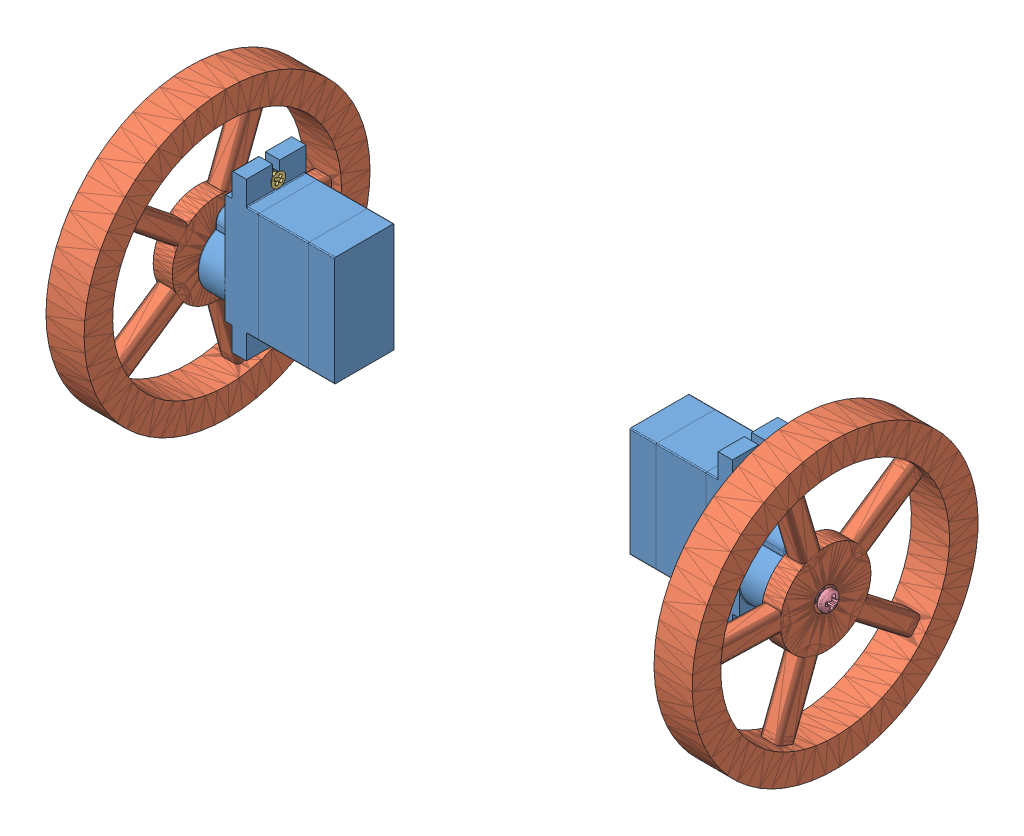
SolidWorks assembly SE, configuration Predeterminado. Lengths in mm.
Overall size (135.6 84.36 84.36).
12 component instances, 4 part files, 0 mates.
Components (placement in the parent):
- Ensamblaje2-1: Ensamblaje2 [Predeterminado] at origin size (36.8 84.36 84.36)
  - servo-1: servo [默认] at (122.5972 -230.0354 146.3432) x (0 1 0) z (0 0 1) size (33 32.3 12.5)
  - FS90R Wheel-1: FS90R Wheel [Predeterminado] at (85.7972 -253.1519 186.3657) x (0 0.626515 0.77941) z (1 0 0) size (60 60 8)
  - M2x6 SelfTap Screw-1: M2x6 SelfTap Screw [Predeterminado] at (104.5972 -216.5354 146.3432) x (0 -0.830265 0.557369) z (1 0 0) size (3.4 3.28 6)
  - (M2_3_mm)_90116A007_METRIC 316 SS PAN HEAD PHILLIPS MACHINE SCREW-1: (M2_3_mm)_90116A007_METRIC 316 SS PAN HEAD PHILLIPS MACHINE SCREW [90116A007] at (90.7972 -235.2854 146.3432) x (0 -0.999434 0.033641) z (-1 0 0) size (4 4 4.68)
  - M2x6 SelfTap Screw-2: M2x6 SelfTap Screw [Predeterminado] at (104.5972 -243.5354 146.3432) x (0 0.77764 -0.62871) z (1 0 0) size (3.4 3.28 6)
- Servo_left-1: Servo_left [Predeterminado] at (5 0 0) size (36.8 84.14 84.14)
  - servo-1: servo [默认] at (179.5972 -230.0354 146.3432) x (0 1 0) z (0 0 -1) size (33 32.3 12.5)
  - FS90R Wheel-1: FS90R Wheel [Predeterminado] at (216.3972 -278.3893 154.2847) x (0 -0.609996 -0.792404) z (-1 0 0) size (60 60 8)
  - (M2_3_mm)_90116A007_METRIC 316 SS PAN HEAD PHILLIPS MACHINE SCREW-1: (M2_3_mm)_90116A007_METRIC 316 SS PAN HEAD PHILLIPS MACHINE SCREW [90116A007] at (211.3972 -235.2854 146.3432) x (0 0.262335 0.964977) z (1 0 0) size (4 4 4.68)
  - M2x6 SelfTap Screw-1: M2x6 SelfTap Screw [Predeterminado] at (197.5972 -216.5354 146.3432) x (0 0.217763 0.976002) z (-1 0 0) size (3.4 3.28 6)
  - M2x6 SelfTap Screw-2: M2x6 SelfTap Screw [Predeterminado] at (197.5972 -243.5354 146.3432) x (0 0.231632 0.972803) z (-1 0 0) size (3.4 3.28 6)
